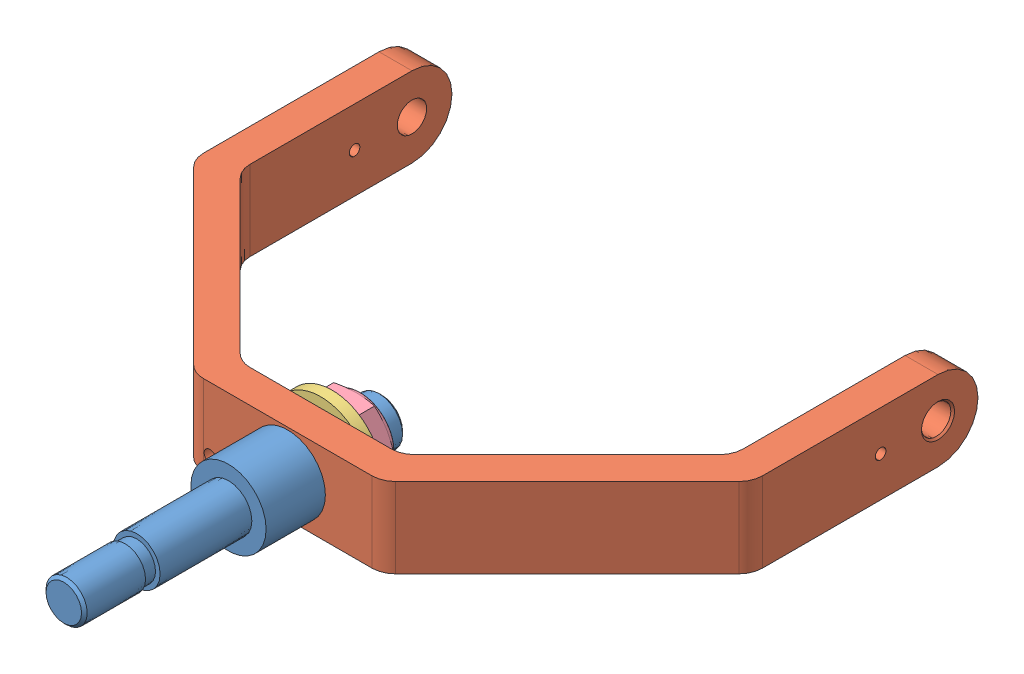
SolidWorks assembly Yoke Assembly (YK), configuration Default. Lengths in mm.
Overall size (150.88 28.57 171.32).
4 component instances, 4 part files, 9 mates.
Components (placement in the parent):
- Yoke Rod (YK-2)-1: Yoke Rod (YK-2) [Default] at (-44.1455 25.2929 -11.4146) size (20.32 20.32 85.85)
- Yoke Fork (YK-1)-1: Yoke Fork (YK-1) [Default] at (-44.1455 14.4979 -65.135) x (1 0 0) z (0 1 0) size (150.88 110.87 21.59)
- SAE 0.5 Washer (MMC 91083A033)-1: SAE 0.5 Washer (MMC 91083A033) [91083A033] at (-44.1455 25.2929 -23.378) x (0 0 1) z (-1 0 0) size (3.07 26.97 26.97)
- Nylok Jam Nut 0.5 (MMC 94945A225)-1: Nylok Jam Nut 0.5 (MMC 94945A225) [94945A225] at (-44.1455 25.2929 -23.378) x (0.866025 0.5 0) z (-0.5 0.866025 0) size (19.05 8.3 22)
Mates (geometry in assembly coordinates):
- Concentric1: concentric aligned: cylinder of Yoke Rod (YK-2)-1 through (-44.1455 25.2929 -17.7646) axis (0 0 1) radius 7.1437; cylinder of Yoke Fork (YK-1)-1 through (-44.1455 25.2929 -122.285) axis (0 0 1) radius 7.1437
- Coincident1: coincident anti-aligned: plane of Yoke Rod (YK-2)-1 through (-44.1455 25.2929 -11.4146) normal (0 0 -1); plane of Yoke Fork (YK-1)-1 through (-69.5455 36.0879 -11.4146) normal (0 0 1)
- Lock1: lock: unknown of Yoke Rod (YK-2)-1; unknown of Yoke Fork (YK-1)-1
- Concentric2: concentric anti-aligned: cylinder of Yoke Rod (YK-2)-1 through (-44.1455 25.2929 -36.8146) axis (0 0 1) radius 6.35; cylinder of SAE 0.5 Washer (MMC 91083A033)-1 through (-44.1455 25.2929 -20.3046) axis (0 0 -1) radius 6.7437
- Coincident2: coincident anti-aligned: plane of Yoke Fork (YK-1)-1 through (-65.8632 36.0879 -20.3046) normal (0 0 -1); plane of SAE 0.5 Washer (MMC 91083A033)-1 through (-44.1455 25.2929 -20.3046) normal (0 0 1)
- Lock2: lock: unknown of Yoke Fork (YK-1)-1; unknown of SAE 0.5 Washer (MMC 91083A033)-1
- Concentric3: concentric aligned: cylinder of Yoke Rod (YK-2)-1 through (-44.1455 25.2929 -36.8146) axis (0 0 1) radius 6.35; cylinder of Nylok Jam Nut 0.5 (MMC 94945A225)-1 through (-44.1455 25.2929 -30.0688) axis (0 0 1) radius 5.7213
- Coincident3: coincident anti-aligned: plane of SAE 0.5 Washer (MMC 91083A033)-1 through (-44.1455 25.2929 -23.378) normal (0 0 -1); plane of Nylok Jam Nut 0.5 (MMC 94945A225)-1 through (-44.1455 6.2429 -23.378) normal (0 0 1)
- Parallel1: parallel aligned: plane of Yoke Fork (YK-1)-1 through (-44.1455 36.0879 -65.135) normal (0 1 0); plane of Nylok Jam Nut 0.5 (MMC 94945A225)-1 through (-49.6448 34.8179 -31.3155) normal (0 1 0)
